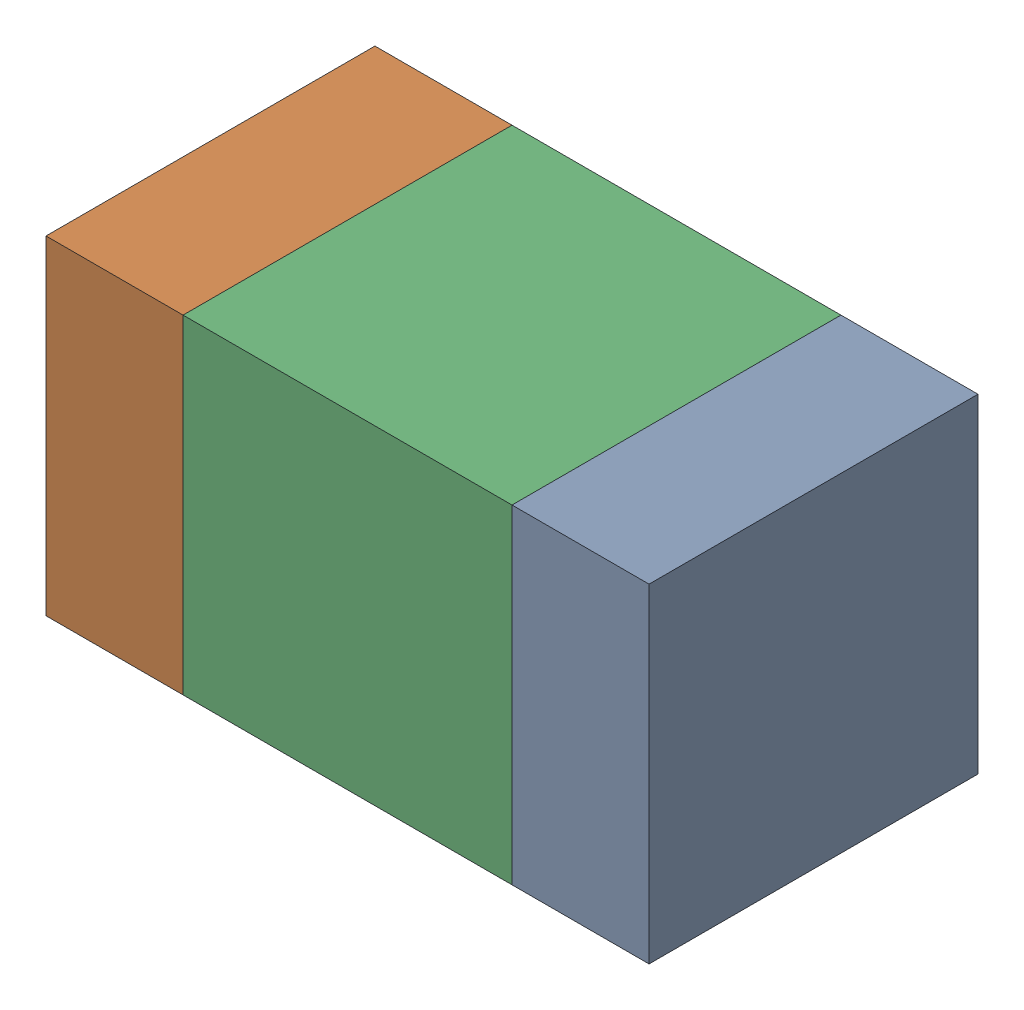
SolidWorks assembly C104_1PCB, configuration Default. Lengths in mm.
Overall size (1.1 0.6 0.6).
6 component instances, 2 part files, 0 mates.
Components (placement in the parent):
- 854785160-1: 854785160 [Default] at (109.025 106.3 0) size (0.25 0.6 0.6)
  - Extruded_19-1: Extruded_19 [Default] at origin size (0.25 0.6 0.6)
- 854785160-2: 854785160 [Default] at (108.175 106.3 0) size (0.25 0.6 0.6)
  - Extruded_19-1: Extruded_19 [Default] at origin size (0.25 0.6 0.6)
- 761606048-1: 761606048 [Default] at (108.6 106.3 0) size (0.6 0.6 0.6)
  - Extruded_9-1: Extruded_9 [Default] at origin size (0.6 0.6 0.6)
